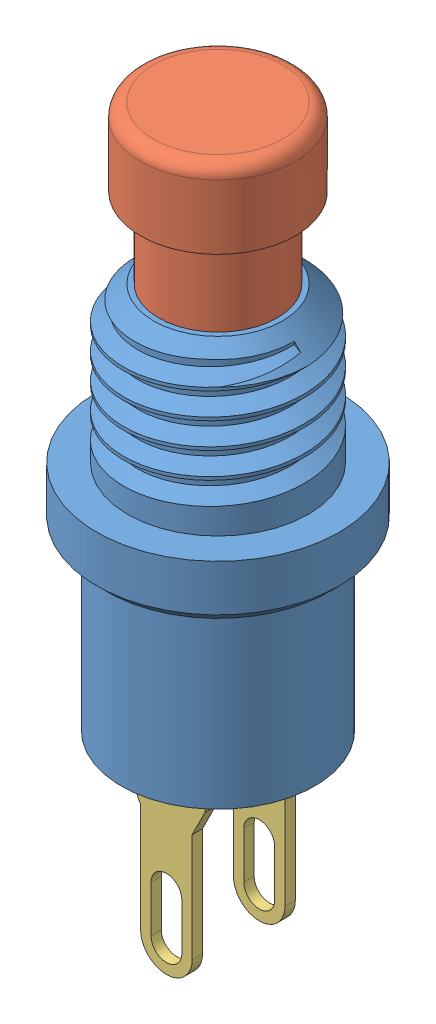
SolidWorks assembly Pushbutton, configuration Default. Lengths in mm.
Overall size (9.4 28.31 9.4).
4 component instances, 3 part files, 5 mates.
Components (placement in the parent):
- body-1: body [Default] x (1 0 0) z (0 -1 0) size (9.4 9.4 15)
- buttoncap-1: buttoncap [Default] at (0 18.1059 0) x (0.991361 0 -0.131163) z (0.131163 0 0.991361) size (6 12 6)
- pin-1: pin [Default] at (0 0 2) x (1 0 0) z (0 1 0) size (3 0.4 7.2)
- pin-2: pin [Default] at (0 0 -1.6) x (1 0 0) z (0 1 0) size (3 0.4 7.2)
Mates (geometry in assembly coordinates):
- Concentric1: concentric aligned: cylinder of body-1 through (0 6 0) axis (0 1 0) radius 2.25; cylinder of buttoncap-1 through (0 9.1059 0) axis (0 1 0) radius 2.3
- Universal Joint1: universal joint: cylinder of buttoncap-1 through (0 9.1059 0) axis (0 1 0) radius 2.3; cylinder of body-1 through (0 6 0) axis (0 1 0) radius 2.25
- Coincident1: coincident anti-aligned: plane of body-1 through (0 0 0) normal (0 -1 0); plane of pin-1 through (0 0 1.6) normal (0 1 0)
- Coincident2: coincident aligned: plane of pin-1 through (0 0 2) normal (1 0 0)
- Symmetric1: symmetric aligned: plane of pin-1 through (0 0 2) normal (0 0 1); plane of pin-2 through (0 0 -2) normal (0 0 -1)
